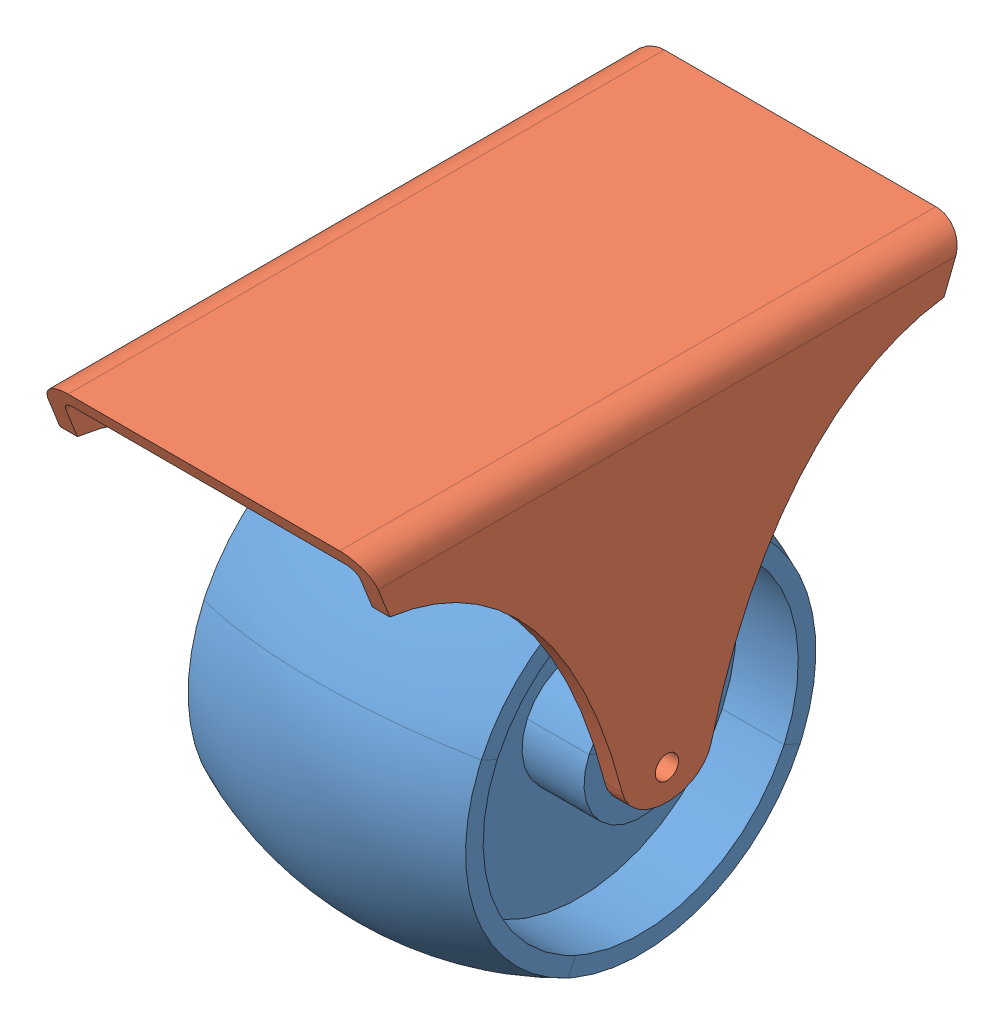
SolidWorks assembly Rolle, configuration Standard. Lengths in mm.
Overall size (28.61 54.54 53.59).
2 component instances, 2 part files, 5 mates.
Components (placement in the parent):
- Rolle-1: Rolle [Standard] at (1010.388 1040.9998 -976.2734) x (1 0 0) z (0 -0.414368 -0.91011) size (23.76 40.47 40.46)
- Rollenhalter-1: Rollenhalter [Standard] at (1010.388 396.1981 1340.927) x (1 0 0) z (0 1 0) size (28.61 51.43 30.62)
Mates (geometry in assembly coordinates):
- Konzentrisch1: concentric anti-aligned: line of Rolle-1 through (-2.2471 -27.5596 -25.5346) axis (-1 0 0); cylinder of Rollenhalter-1 through (-28.4323 -27.5596 -25.5346) axis (1 0 0) radius 1
- Abstand1: distance = 0.747 mm anti-aligned: plane of Rollenhalter-1 through (-1.5 -33.777 11.9036) normal (-1 0 0); plane of Rolle-1 through (-2.2471 -28.3625 -27.2982) normal (1 0 0)
- Deckungsgleich2: coincident aligned: plane of Rollenhalter-1 through (-25.7536 0 1.8039) normal (0 1 0); plane of assembly through (0 0 0) normal (0 1 0)
- Deckungsgleich3: coincident: line of Rollenhalter-1 through (23.2536 -25.7536 0) axis (0 1 0); plane of assembly
- Deckungsgleich4: coincident aligned: plane of Rollenhalter-1 through (0 -30.1719 -0.5799) normal (1 0 0); plane of assembly through (0 0 0) normal (1 0 0)
